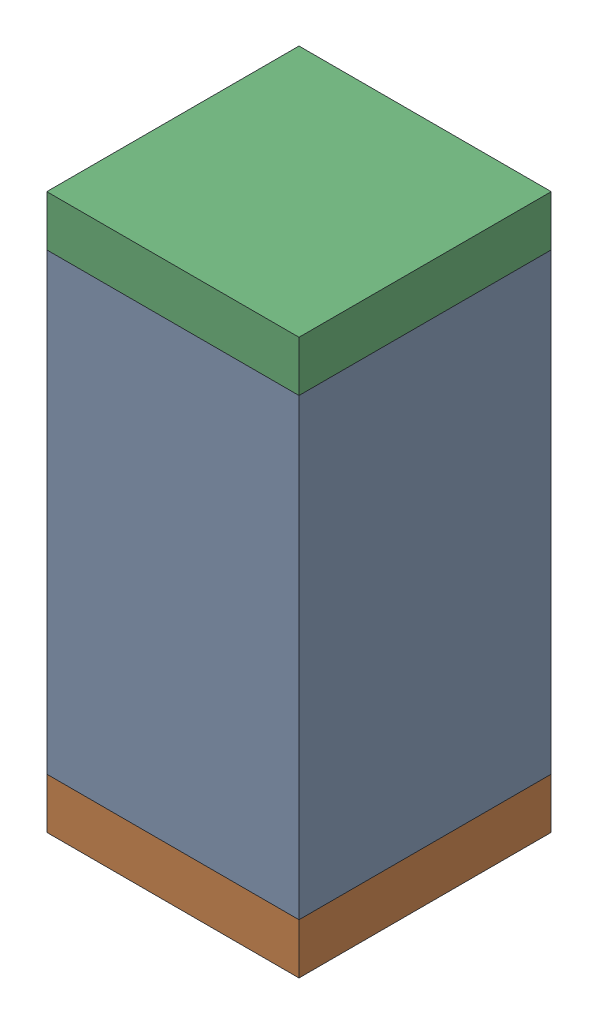
SolidWorks assembly C44, configuration Default. Lengths in mm.
Overall size (0.5 1.1 0.5).
6 component instances, 2 part files, 0 mates.
Components (placement in the parent):
- 791586336-1: 791586336 [Default] at (134.6 38 0) size (0.5 0.9 0.5)
  - Extruded_8-1: Extruded_8 [Default] at origin size (0.5 0.9 0.5)
- 810157360-1: 810157360 [Default] at (134.6 37.5 0) size (0.5 0.1 0.5)
  - Extruded_9-1: Extruded_9 [Default] at origin size (0.5 0.1 0.5)
- 810157360-2: 810157360 [Default] at (134.6 38.5 0) size (0.5 0.1 0.5)
  - Extruded_9-1: Extruded_9 [Default] at origin size (0.5 0.1 0.5)
